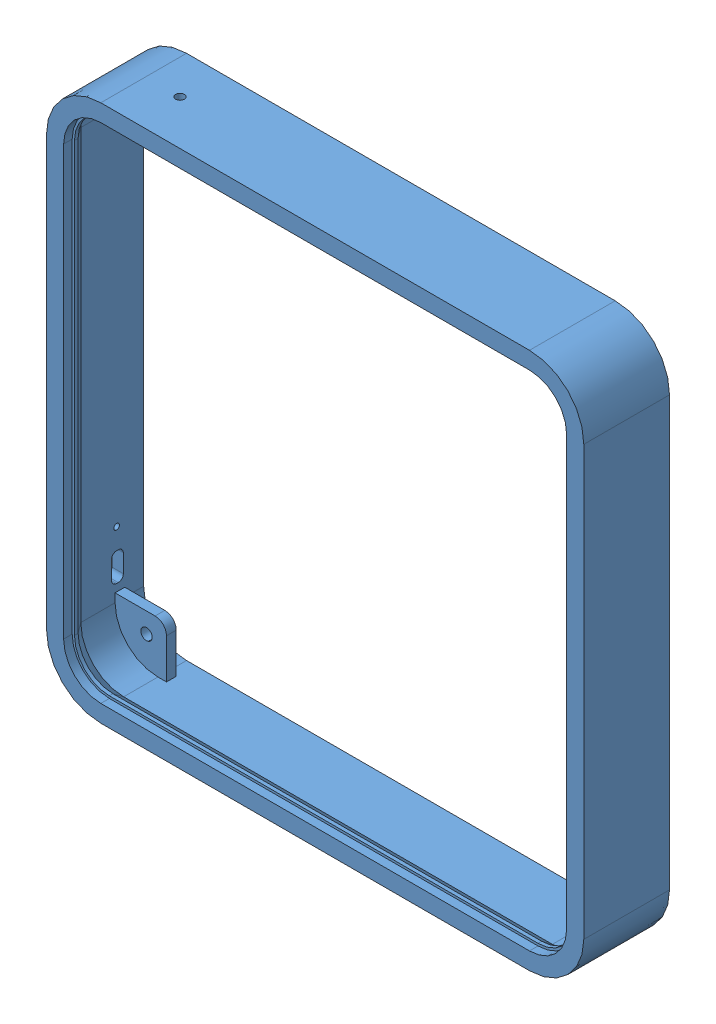
SolidWorks assembly Assembly-lite, configuration Default. Lengths in mm.
Overall size (190 190 30).
2 component instances, 2 part files, 4 mates.
Components (placement in the parent):
- frame-lite-1: frame-lite [Default] at origin size (188 188 30)
- Part2^Assembly-lite-1: Part2^Assembly-lite [Default] at origin size (180 180 0) (virtual)
Mates (geometry in assembly coordinates):
- InPlace1: in place: plane of ? through (0 0 0) normal (0 0 -1); plane of ? through (0 0 0) normal (0 0 -1); moOrthogonalPlaneRef_w of ? through (0 0 0) normal (0 0 -1); plane of ? through (0 0 0) normal (0 1 0); plane of ? through (0 0 0) normal (0 0 -1); plane of ? through (0 0 0) normal (-1 0 0); plane of ? through (0 0 0) normal (0 0 -1); unknown of ?
- Coincident1: coincident aligned: plane of frame-lite-1; plane of ?
- Coincident2: coincident aligned: moOrthogonalPlaneRef_w of frame-lite-1 through (0 0 0) normal (0 1 0); plane of regioni^Assem1-1 through (0 0 0) normal (0 1 0)
- Coincident3: coincident anti-aligned: moOrthogonalPlaneRef_w of frame-lite-1 through (0 0 0) normal (1 0 0); plane of regioni^Assem1-1 through (0 0 0) normal (-1 0 0)
